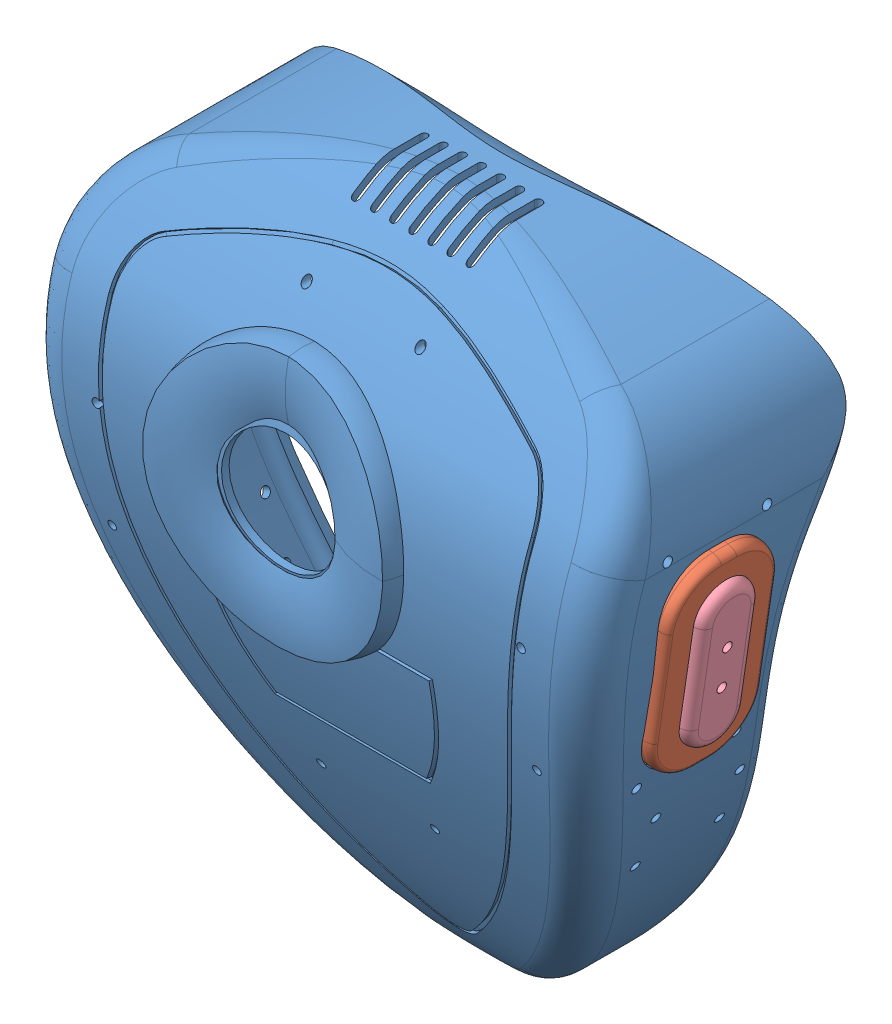
SolidWorks assembly left holder, configuration Default. Lengths in mm.
Overall size (340.09 381.81 204.11).
6 component instances, 5 part files, 12 mates.
Components (placement in the parent):
- backpack 2g botttom-1: backpack 2g botttom [Default] at (96.2333 213.173 256.1836) size (340.09 381.81 204.11)
- Part2-1: Part2 [Default] at (246.1823 217.7312 331.1836) x (0.147081 0.989124 0) z (0 0 1) size (104.05 10.05 58.05)
- Part2-2: Part2 [Default] at (-53.7159 217.7312 331.1836) x (0.14708 -0.989125 0) z (0 0 1) size (104.05 10.05 58.05)
- Pieza soporte bocina izquierda-1: Pieza soporte bocina izquierda [Default] at (226.5632 221.7718 330.6859) x (0.989124 -0.147081 0) z (0 0 1) size (30.45 130 93.17)
- Seguro bocina izquierda-1: Seguro bocina izquierda [Default] at (237.5596 193.7385 331.1836) x (0 0 -1) z (-0.147081 -0.989124 0) size (30 10.46 80)
- Union left-2: Union left [Default] at (207.6424 127.8836 316.1993) x (0.008119 -0.003198 -0.999962) z (0.930382 -0.366487 0.008727) size (60 40 6.53)
Mates (geometry in assembly coordinates):
- Coincident1: coincident anti-aligned: plane of backpack 2g botttom-1 through (-73.3837 191.173 360.1836) normal (0 0 -1); plane of Part2-1 through (240.2622 245.9084 360.1836) normal (0 0 1)
- Coincident2: coincident: point of backpack 2g botttom-1; unknown of Part2-1
- Coincident4: coincident: curve of backpack 2g botttom-1; unknown of Part2-1
- Coincident5: coincident anti-aligned: plane of backpack 2g botttom-1 through (-73.3837 191.173 360.1836) normal (0 0 -1); plane of Part2-2 through (-39.8535 192.4957 360.1836) normal (0 0 1)
- Coincident6: coincident: unknown of backpack 2g botttom-1; unknown of Part2-2
- Coincident7: coincident: edge_curve of backpack 2g botttom-1; unknown of Part2-2
- Distance1: distance = 5 mm anti-aligned: plane of Pieza soporte bocina izquierda-1 through (241.4 219.5656 330.6859) normal (0.989124 -0.147081 0); plane of Part2-1 through (232.3198 192.4957 327.1836) normal (-0.989124 0.147081 0)
- Concentric1: concentric aligned: cylinder of backpack 2g botttom-1 through (308.1225 266.2598 356.6859) axis (-0.989124 0.147081 0) radius 2.5; cylinder of Pieza soporte bocina izquierda-1 through (249.6366 274.9565 356.6859) axis (-0.989124 0.147081 0) radius 2.5
- Concentric2: concentric aligned: cylinder of backpack 2g botttom-1 through (308.1225 266.2598 304.6859) axis (-0.989124 0.147081 0) radius 2.5; cylinder of Pieza soporte bocina izquierda-1 through (249.6366 274.9565 304.6859) axis (-0.989124 0.147081 0) radius 2.5
- Concentric3: concentric aligned: cylinder of Pieza soporte bocina izquierda-1 through (219.4917 211.5901 331.1836) axis (0.989124 -0.147081 0) radius 2.5; cylinder of Seguro bocina izquierda-1 through (239.3115 208.6429 331.1836) axis (0.989124 -0.147081 0) radius 2.5
- Concentric4: concentric aligned: cylinder of Pieza soporte bocina izquierda-1 through (222.4333 231.3726 331.1836) axis (0.989124 -0.147081 0) radius 2.5; cylinder of Seguro bocina izquierda-1 through (242.2532 228.4254 331.1836) axis (0.989124 -0.147081 0) radius 2.5
- Coincident11: coincident anti-aligned: plane of Pieza soporte bocina izquierda-1 through (241.4 219.5656 330.6859) normal (0.989124 -0.147081 0); plane of Seguro bocina izquierda-1 through (237.5596 193.7385 331.1836) normal (-0.989124 0.147081 0)
